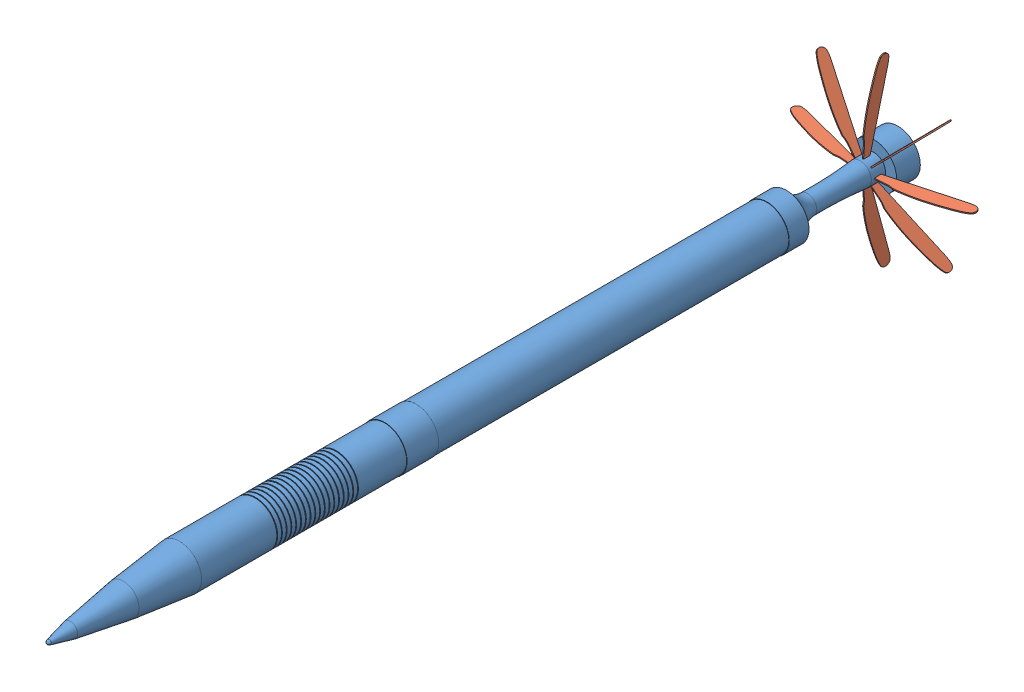
SolidWorks assembly S-5, configuration Default. Lengths in mm.
Overall size (232.55 232.55 1200).
9 component instances, 2 part files, 6 mates.
Components (placement in the parent):
- S-5Body-1: S-5Body [Default] at origin size (57 57 1078)
- S-5Stab-1: S-5Stab [Default] at (-0.5758 14.4588 -1033.7314) x (0.999575 0 -0.029143) z (0.029143 0 0.999575) size (1.4 101.82 33.09)
- S-5Stab-9: S-5Stab [Default] at (-10.6311 9.8167 -1033.7314) x (0.706806 0.706806 -0.029143) z (0.020607 0.020607 0.999575) size (1.4 101.82 33.09)
- S-5Stab-10: S-5Stab [Default] at (-14.4588 -0.5758 -1033.7314) x (0 0.999575 -0.029143) z (0 0.029143 0.999575) size (1.4 101.82 33.09)
- S-5Stab-11: S-5Stab [Default] at (-9.8167 -10.6311 -1033.7314) x (-0.706806 0.706806 -0.029143) z (-0.020607 0.020607 0.999575) size (1.4 101.82 33.09)
- S-5Stab-12: S-5Stab [Default] at (0.5758 -14.4588 -1033.7314) x (-0.999575 0 -0.029143) z (-0.029143 0 0.999575) size (1.4 101.82 33.09)
- S-5Stab-13: S-5Stab [Default] at (10.6311 -9.8167 -1033.7314) x (-0.706806 -0.706806 -0.029143) z (-0.020607 -0.020607 0.999575) size (1.4 101.82 33.09)
- S-5Stab-14: S-5Stab [Default] at (14.4588 0.5758 -1033.7314) x (0 -0.999575 -0.029143) z (0 -0.029143 0.999575) size (1.4 101.82 33.09)
- S-5Stab-15: S-5Stab [Default] at (9.8167 10.6311 -1033.7314) x (0.706806 -0.706806 -0.029143) z (0.020607 -0.020607 0.999575) size (1.4 101.82 33.09)
Mates (geometry in assembly coordinates):
- Coincident13: coordinate: point of S-5Body-1
- Coincident14: coincident aligned: plane of S-5Body-1 through (0 0 0) normal (0 1 0)
- Angle2: planar angle = 0.029147 rad aligned: plane of S-5Stab-1 through (-0.5758 14.4588 -1033.7314) normal (0.999575 0 -0.029143); plane of S-5Body-1 through (0 0 0) normal (1 0 0)
- Coincident15: coincident aligned: cylinder of S-5Body-1 through (0 9 -1038) axis (0 1 0) radius 0.25; circle of S-5Stab-1
- Concentric2: concentric aligned: cylinder of S-5Body-1 through (0 9 -1038) axis (0 1 0) radius 0.25; cylinder of S-5Stab-1 through (0 14.4588 -1038) axis (0 1 0) radius 0.25
- Tangent3: tangent anti-aligned: cylinder of S-5Body-1 through (0 0 0) axis (0 0 1) radius 14.4588; plane of S-5Stab-1 through (0.5758 14.4588 -1042.2686) normal (0 -1 0)
